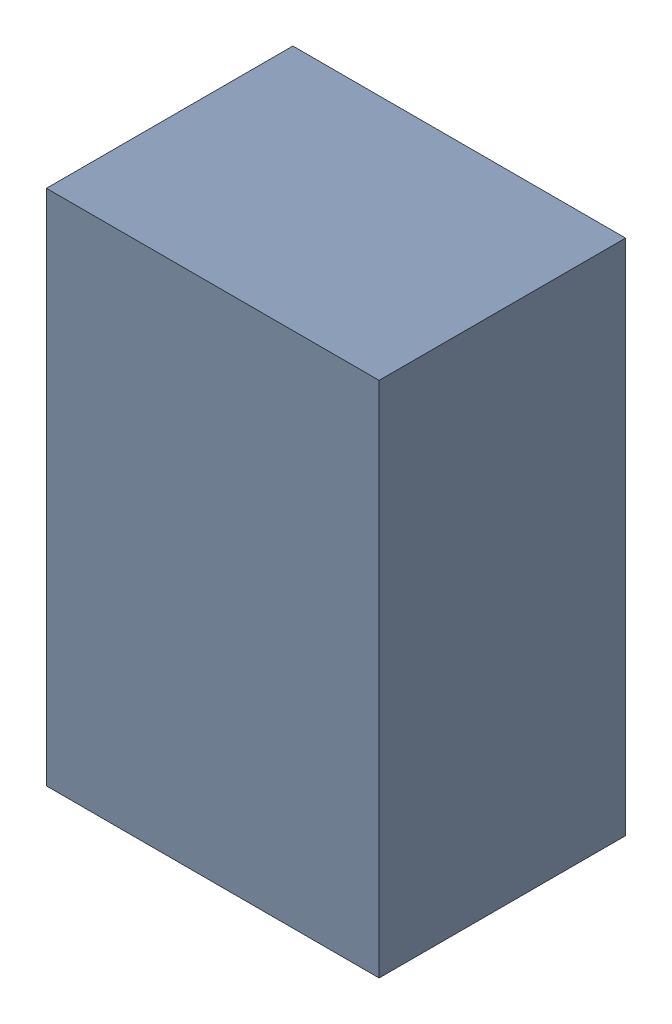
SolidWorks assembly U17, configuration ﾃﾞﾌｫﾙﾄ. Lengths in mm.
Overall size (1.35 2.1 1).
2 component instances, 1 part files, 0 mates.
Components (placement in the parent):
- 689262600-1: 689262600 [ﾃﾞﾌｫﾙﾄ] at (39.25 56.25 0) size (1.35 2.1 1)
  - Extruded_41-1: Extruded_41 [ﾃﾞﾌｫﾙﾄ] at origin size (1.35 2.1 1)
